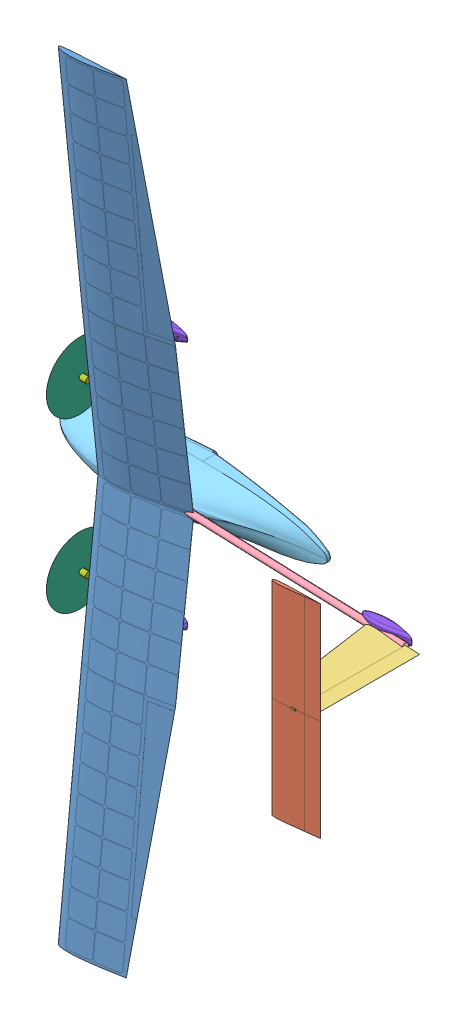
SolidWorks assembly seaway_mini, configuration Default. Lengths in mm.
Overall size (1952.61 3852.94 833.67).
18 component instances, 11 part files, 22 mates.
Components (placement in the parent):
- Wing-1: Wing [Default] at origin size (425.27 3852.94 282.57)
- HStab-1: HStab [Default] at origin size (227.63 1000.48 27.43)
- VStab-1: VStab [Default] at origin size (266.38 26.61 545.48)
- Boom^seaway_mini-1: Boom^seaway_mini [Default] at origin size (1393.35 30.1 80.08) (virtual)
- pod_only-1: pod_only [Default] at (-90.5553 0 -207.4429) size (1282.5 228.44 283.6)
- Propeller^seaway_mini-1: Propeller^seaway_mini [Default] at origin size (0 330.2 330.2) (virtual)
- Motor-1: Motor [Default] at (-105.755 414.69 62.2431) x (0 1 0) z (0 0 1) size (28 45.1 28)
- Sponson Placeholder-1: Sponson Placeholder [Default] at (160 611.2893 -159.0378) x (0 -0.994522 -0.104528) z (-1 0 0) size (68.09 62.41 243.69)
- Sponson Placeholder-2: Sponson Placeholder [Default] at (1393.89 0 -30) x (0 -1 0) z (-1 0 0) size (68.09 62.41 243.69)
- Propeller^seaway_mini-2: Propeller^seaway_mini [Default] at (0 0 124.4863) x (1 0 0) z (0 0 -1) size (0 330.2 330.2) (virtual)
- Motor-2: Motor [Default] at (-105.755 -414.69 62.2431) x (0 -1 0) z (0 0 -1) size (28 45.1 28)
- Sponson Placeholder-4: Sponson Placeholder [Default] at (160 -611.2893 -159.0378) x (0 -0.994522 0.104528) z (-1 0 0) size (68.09 62.41 243.69)
- Inboard Sponson Mount^seaway_mini-3: Inboard Sponson Mount^seaway_mini [Default] at origin size (34.95 108.05 184.26) (virtual)
- Outboard Sponson Mount^seaway_mini-3: Outboard Sponson Mount^seaway_mini [Default] at origin size (34.96 73.14 213.76) (virtual)
- Aft Sponson Mount^seaway_mini-1: Aft Sponson Mount^seaway_mini [Default] at origin size (5.47 25.97 200.27) (virtual)
- Inboard Sponson Mount^seaway_mini-5: Inboard Sponson Mount^seaway_mini [Default] at (-30 -1072.8162 -79.8492) x (-1 0 0) z (0 0 -1) size (34.95 108.05 184.26) (virtual)
- Outboard Sponson Mount^seaway_mini-5: Outboard Sponson Mount^seaway_mini [Default] at (-30 -1324.2632 -41.1099) x (-1 0 0) z (0 0 -1) size (34.96 73.14 213.76) (virtual)
- Aft Sponson Mount^seaway_mini-2: Aft Sponson Mount^seaway_mini [Default] at (249.5338 -1199.404 -97.5848) x (-1 0 0) z (0 0 -1) size (5.47 25.97 200.27) (virtual)
Mates (geometry in assembly coordinates):
- Coincident1: coincident aligned: plane of pod_only-1 through (-90.5553 0 -207.4429) normal (0 1 0)
- Parallel1: parallel aligned: plane of pod_only-1 through (-90.5553 0 -207.4429) normal (0 0 1)
- Distance1: distance = 448.93 mm: point of pod_only-1
- Coincident4: coincident aligned: plane of Wing^seaway_mini-1 through (0 0 26) normal (0 1 0)
- Parallel2: parallel aligned: plane of Wing^seaway_mini-1 through (0 0 26) normal (0 0 1)
- Coincident6: coincident: unknown of Wing^seaway_mini-1
- Distance3: distance = 26 mm: plane of Wing^seaway_mini-1 through (0 0 26) normal (0 0 1)
- Coincident7: coordinate: unknown of VStab-1
- Coincident13: coordinate: unknown of HStab-1
- Coincident14: coordinate: unknown of Wing-1
- Coincident17: coincident: unknown of pod_only-1
- Concentric1: concentric anti-aligned: circle of Propeller^seaway_mini-1; cylinder of Propdrive v2 2830 800 kv Motor-1 through (-136.755 414.69 62.2431) axis (1 0 0) radius 14
- Distance5: distance = 10 mm aligned: plane of Propdrive v2 2830 800 kv Motor-1 through (-136.755 414.69 62.2431) normal (-1 0 0); plane of Propeller^seaway_mini-1 through (-146.755 414.69 62.2431) normal (-1 0 0)
- Parallel6: parallel aligned: plane of Sponson Placeholder-1 through (160 611.2893 -159.0378) normal (0 -0.104528 0.994522); plane of Wing-1 through (0 0 0) normal (0 -0.104528 0.994522)
- Coincident21: coincident: point of pod_only-1; plane of Sponson Placeholder-1 through (160 611.2893 -159.0378) normal (0 -0.104528 0.994522)
- Distance6: distance = 80 mm: unknown of Sponson Placeholder-1
- Parallel7: parallel aligned: plane of Sponson Placeholder-2 through (1393.89 0 -30) normal (0 0 1)
- Coincident24: coincident anti-aligned: plane of Sponson Placeholder-2 through (1393.89 0 -30) normal (0 -1 0)
- Distance8: distance = 30 mm: unknown of Sponson Placeholder-2
- Coincident26: coincident: plane of Boom^seaway_mini-1 through (1392.2991 0 14.2977) normal (0.999356 0 0.035889); point of Sponson Placeholder-2
- Parallel9: parallel anti-aligned: plane of Sponson Placeholder-1 through (160 611.2893 -159.0378) normal (-1 0 0)
- Distance9: distance = 500 mm: point of pod_only-1; plane of Sponson Placeholder-1 through (160 611.2893 -159.0378) normal (0 -0.994522 -0.104528)
